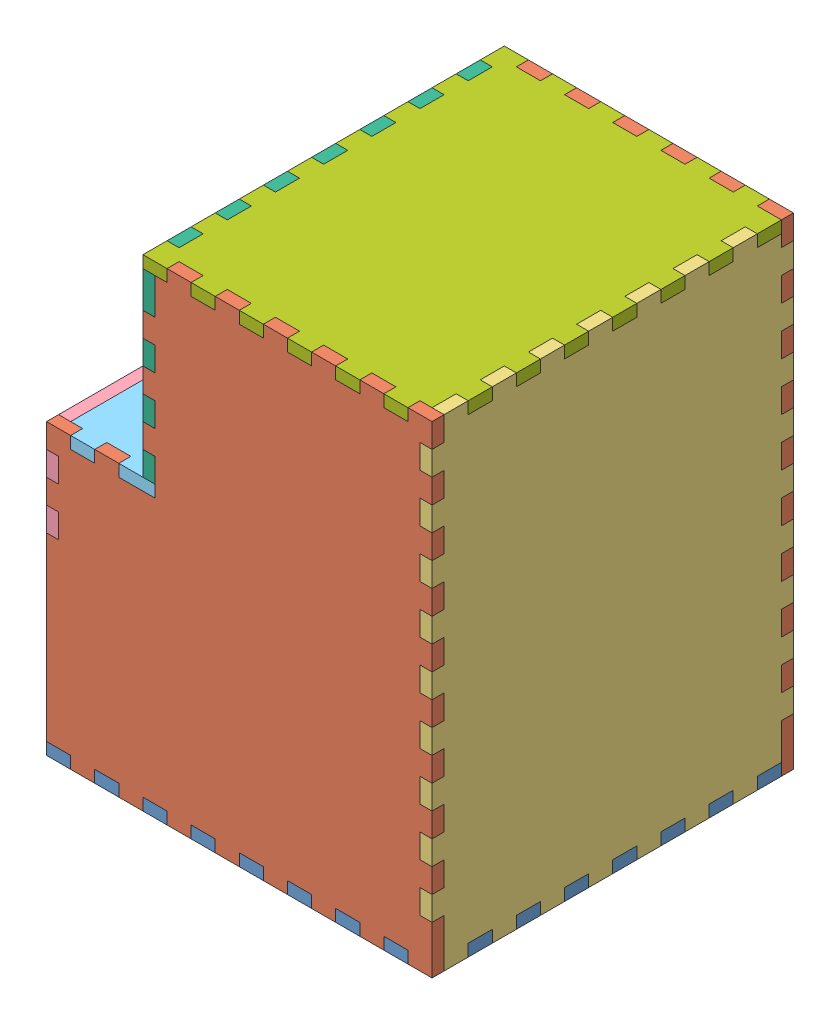
SolidWorks assembly LockBox, configuration Default. Lengths in mm.
Overall size (203.2 254 190.5).
9 component instances, 8 part files, 18 mates.
Components (placement in the parent):
- Bottom-2: Bottom [Default] at (89.6613 95.2889 163.8245) size (203.2 6.35 190.5)
- Side-3: Side [Default] at (89.6613 222.2889 259.0745) x (-1 0 0) z (0 -1 0) size (203.2 6.35 254)
- Side-4: Side [Default] at (89.6613 222.2889 74.9245) x (-1 0 0) z (0 -1 0) size (203.2 6.35 254)
- Back-3: Back [Default] at (191.2613 222.2889 163.8245) x (-1 0 0) z (0 0 -1) size (6.35 254 190.5)
- Front1-1: Front1 [Default] at (-11.9387 222.2889 163.8245) x (0 0 -1) z (1 0 0) size (190.5 50.8 6.35)
- Top1-1: Top1 [Default] at (19.8113 247.6889 163.8245) x (0 0 -1) z (0 -1 0) size (190.5 50.8 6.35)
- Front2-2: Front2 [Default] at (45.2113 295.3139 163.8245) x (0 0 -1) z (-1 0 0) size (190.5 107.95 6.35)
- Top2-1: Top2 [Default] at (115.0613 342.9389 163.8245) x (0 0 1) z (0 1 0) size (190.5 152.4 6.35)
- Door-1: Door [Default] at (-5.5887 149.2639 163.8245) x (0 0 -1) z (-1 0 0) size (177.8 95.25 6.35)
Mates (geometry in assembly coordinates):
- Coincident3: coincident aligned: line of Bottom-2 through (13.4613 101.6389 259.0745) axis (1 0 0); line of Side-3 through (13.4613 101.6389 259.0745) axis (1 0 0)
- Coincident4: coincident: point of Bottom-2; point of Side-3
- Coincident6: coincident anti-aligned: line of Bottom-2 through (13.4613 101.6389 259.0745) axis (0 -1 0); line of Side-3 through (13.4613 95.2889 259.0745) axis (0 1 0)
- Coincident7: coincident: point of Bottom-2; point of Side-4
- Coincident8: coincident: point of Side-4; point of Bottom-2
- Coincident9: coincident anti-aligned: line of Bottom-2 through (178.5613 101.6389 68.5745) axis (-1 0 0); line of Side-4 through (165.8613 101.6389 68.5745) axis (1 0 0)
- Coincident10: coincident: point of Side-3; point of Back-3
- Coincident11: coincident anti-aligned: line of Bottom-2 through (191.2613 101.6389 214.6245) axis (0 0 -1); line of Back-3 through (191.2613 101.6389 201.9245) axis (0 0 1)
- Coincident12: coincident anti-aligned: line of Side-4 through (-5.5887 209.5889 68.5745) axis (0 -1 0); line of Front1-1 through (-5.5887 196.8889 68.5745) axis (0 1 0)
- Coincident13: coincident aligned: line of Side-4 through (-11.9387 234.9889 74.9245) axis (0 0 -1); line of Front1-1 through (-11.9387 234.9889 74.9245) axis (0 0 -1)
- Coincident17: coincident anti-aligned: line of Side-4 through (13.4613 241.3389 68.5745) axis (-1 0 0); line of Top1-1 through (0.7613 241.3389 68.5745) axis (1 0 0)
- Coincident18: coincident anti-aligned: line of Front1-1 through (-5.5887 247.6889 74.9245) axis (0 0 1); line of Top1-1 through (-5.5887 247.6889 252.7245) axis (0 0 -1)
- Coincident24: coincident aligned: line of Side-4 through (45.2113 342.9389 68.5745) axis (0 -1 0); line of Front2-2 through (45.2113 342.9389 68.5745) axis (0 -1 0)
- Coincident25: coincident anti-aligned: line of Side-4 through (38.8613 260.3889 68.5745) axis (1 0 0); line of Front2-2 through (45.2113 260.3889 68.5745) axis (-1 0 0)
- Coincident26: coincident: point of Front2-2; point of Top2-1
- Coincident27: coincident anti-aligned: line of Side-4 through (51.5613 349.2889 74.9245) axis (1 0 0); line of Top2-1 through (64.2613 349.2889 74.9245) axis (-1 0 0)
- Coincident28: coincident anti-aligned: line of Side-4 through (-11.9387 101.6389 74.9245) axis (0 1 0); line of Door-1 through (-11.9387 196.8889 74.9245) axis (0 -1 0)
- Coincident29: coincident aligned: line of Bottom-2 through (-11.9387 101.6389 68.5745) axis (0 0 1); line of Door-1 through (-11.9387 101.6389 74.9245) axis (0 0 1)
